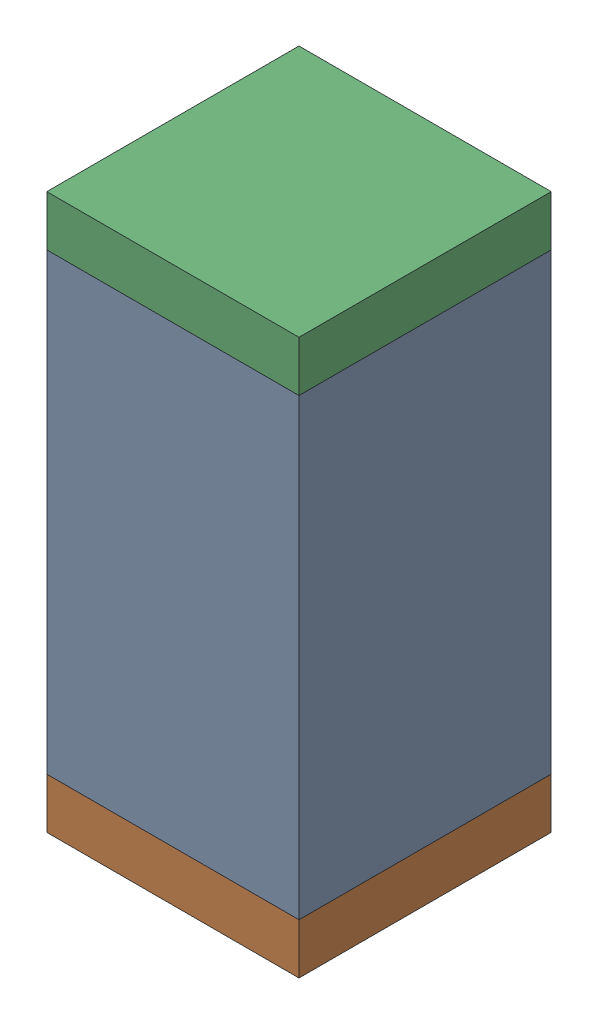
SolidWorks assembly C92, configuration Default. Lengths in mm.
Overall size (0.5 1.1 0.5).
6 component instances, 2 part files, 0 mates.
Components (placement in the parent):
- 791586336-1: 791586336 [Default] at (112.4 65.85 0) size (0.5 0.9 0.5)
  - Extruded_8-1: Extruded_8 [Default] at origin size (0.5 0.9 0.5)
- 810157360-1: 810157360 [Default] at (112.4 65.35 0) size (0.5 0.1 0.5)
  - Extruded_9-1: Extruded_9 [Default] at origin size (0.5 0.1 0.5)
- 810157360-2: 810157360 [Default] at (112.4 66.35 0) size (0.5 0.1 0.5)
  - Extruded_9-1: Extruded_9 [Default] at origin size (0.5 0.1 0.5)
